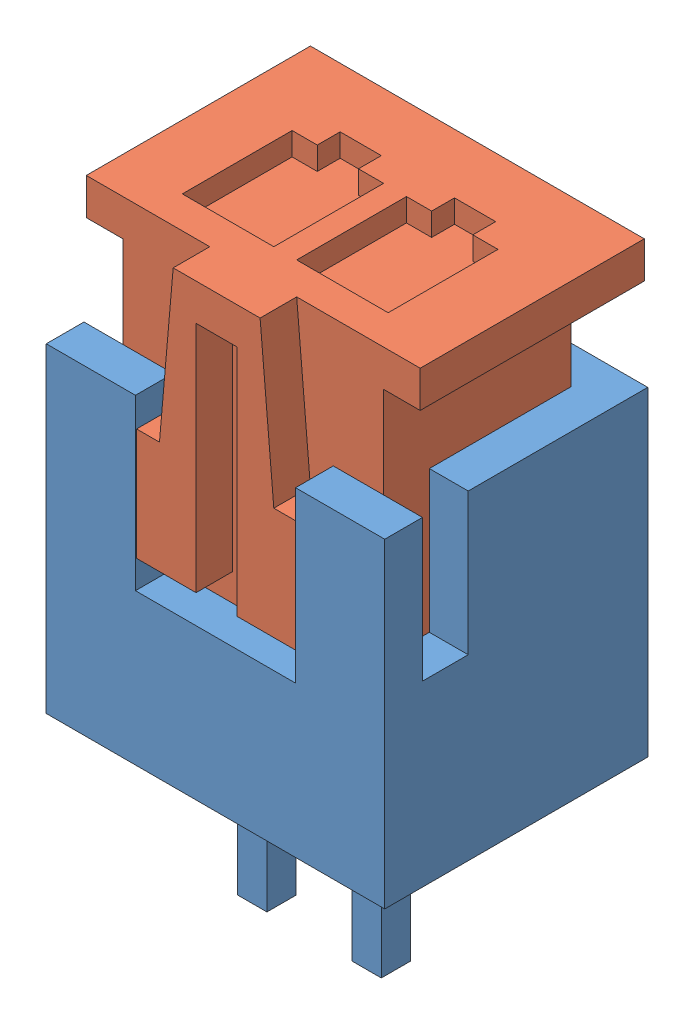
SolidWorks assembly Assem1, configuration Default. Lengths in mm.
Overall size (7.4 13.2 5.75).
2 component instances, 2 part files, 4 mates.
Components (placement in the parent):
- B2B-XH-A-1: B2B-XH-A [Default] at origin size (7.4 10.4 5.75)
- XHP-2-1: XHP-2 [Default] at (0 5.93 -2.85) size (7.3 7.75 5.7)
Mates (geometry in assembly coordinates):
- Coincident1: coordinate: point of B2B-XH-A-1; point of assembly
- Distance1: distance = 9.8 mm: plane of XHP-2-1 through (-2.85 9.8 -2.05) normal (0 1 0); plane of B2B-XH-A-1 through (3.7 0 2.875) normal (0 -1 0)
- Coincident3: coincident: plane of B2B-XH-A-1 through (-2.85 2.3 -2.05) normal (0 0 1); plane of XHP-2-1 through (-3.8092 2.05 -2.05) normal (0 0 -1)
- Coincident4: coincident: plane of B2B-XH-A-1 through (2.85 2.3 2.05) normal (-1 0 0); plane of XHP-2-1 through (2.85 9.8 -2.05) normal (1 0 0)
